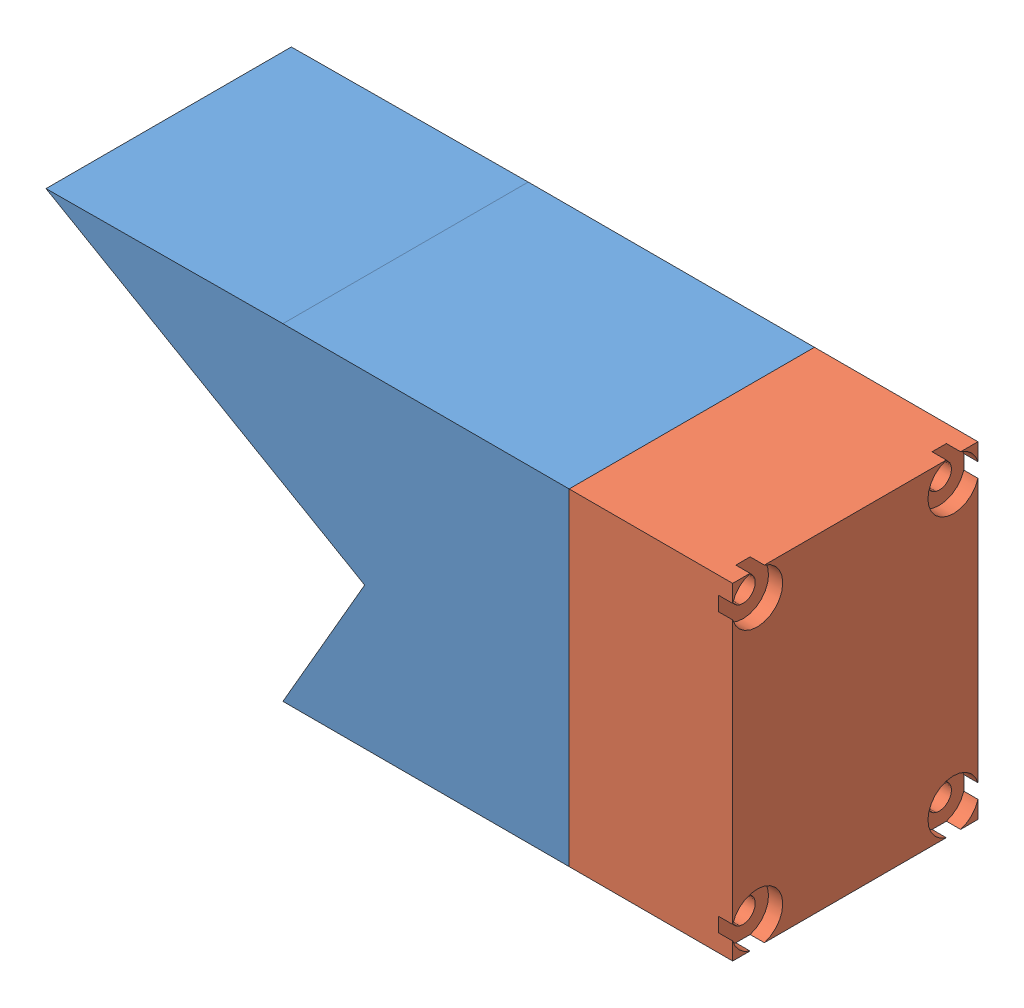
SolidWorks assembly Nacelle Assembly, configuration Default. Lengths in mm.
Overall size (106.64 50.8 38.1).
2 component instances, 2 part files, 3 mates.
Components (placement in the parent):
- Calf Nacelle-1: Calf Nacelle [Default] at (1.6936 15.1916 38.1993) size (81.24 50.8 38.1)
- MotorEndcap-1: MotorEndcap [Default] at (5.6235 2.2988 24.7342) x (0 0 -1) z (1 0 0) size (38.1 50.8 25.4)
Mates (geometry in assembly coordinates):
- Concentric1: concentric anti-aligned: circle of Calf Nacelle-1; circle of ?
- Coincident1: coincident anti-aligned: line of Calf Nacelle-1 through (5.6235 -9.2536 76.2993) axis (0 1 0); line of MotorEndcap-1 through (5.6235 41.5464 76.2993) axis (0 -1 0)
- Coincident2: coincident anti-aligned: line of Calf Nacelle-1 through (5.6235 41.5464 76.2993) axis (0 0 -1); line of MotorEndcap-1 through (5.6235 41.5464 38.1993) axis (0 0 1)
